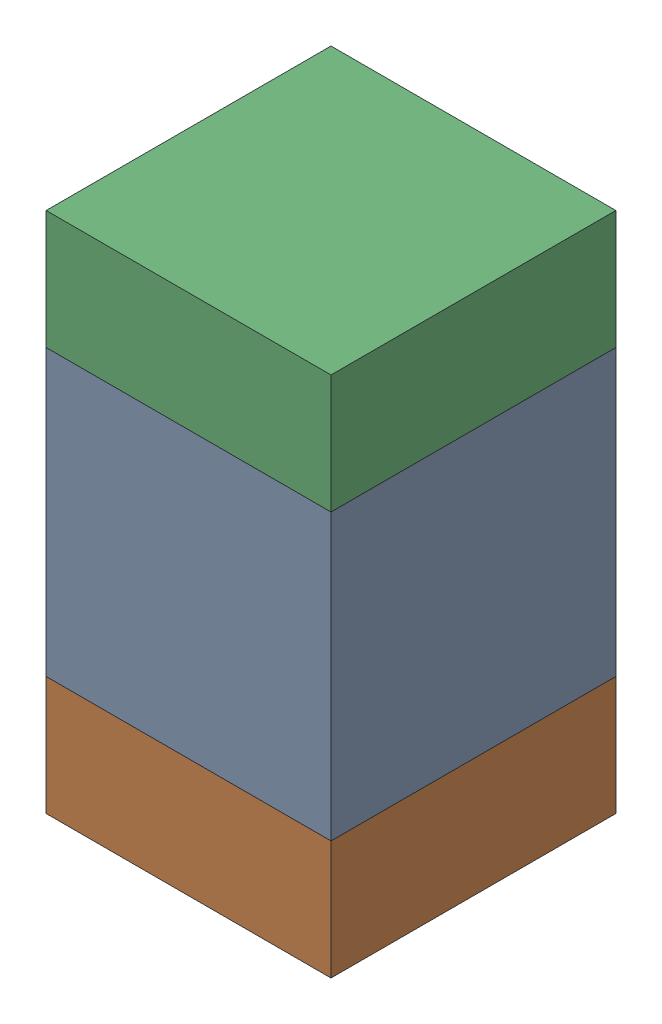
SolidWorks assembly C429PCB, configuration Default. Lengths in mm.
Overall size (0.6 1.1 0.6).
6 component instances, 2 part files, 0 mates.
Components (placement in the parent):
- 761606048-1: 761606048 [Default] at (124.4 88 -2.2638) size (0.6 0.6 0.6)
  - Extruded_9-1: Extruded_9 [Default] at origin size (0.6 0.6 0.6)
- 854785296-1: 854785296 [Default] at (124.4 87.575 -2.2638) size (0.6 0.25 0.6)
  - Extruded_10-1: Extruded_10 [Default] at origin size (0.6 0.25 0.6)
- 854785296-2: 854785296 [Default] at (124.4 88.425 -2.2638) size (0.6 0.25 0.6)
  - Extruded_10-1: Extruded_10 [Default] at origin size (0.6 0.25 0.6)
